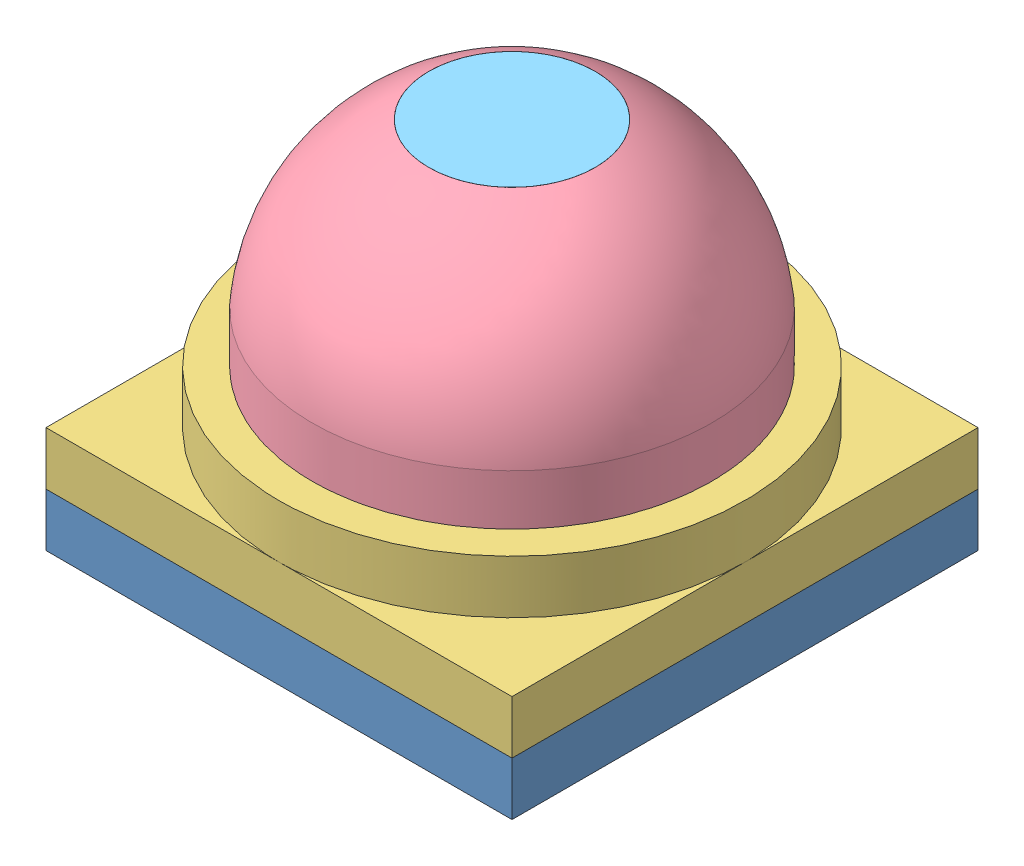
SolidWorks assembly Magnetic Force Sensor Assembly, configuration Default. Lengths in mm.
Overall size (15.86 11.22 15.86).
5 component instances, 5 part files, 9 mates.
Components (placement in the parent):
- PCB with O-Ring-1: PCB with O-Ring [Default] at (5.9128 5.0008 11.2365) size (14 2.1 14)
- MLX90393 Magnetometer-1: MLX90393 Magnetometer [Default] at (5.9128 6.6008 11.2365) x (0 0 1) z (-1 0 0) size (2.1 0.56 2.6)
- Elastomer PCB Interface-1: Elastomer PCB Interface [Default] at (5.9128 6.6008 11.2365) size (14 3.2 14)
- Silicon Elastomer-1: Silicon Elastomer [Default] at (5.9128 8.3185 11.2365) x (0.912613 0 -0.408824) z (0 -1 0) size (12 12 7.9)
- Neodymium Magnet-1: Neodymium Magnet [Default] at (5.9128 14.2185 11.2365) size (5 2 5)
Mates (geometry in assembly coordinates):
- Coincident1: coincident anti-aligned: plane of PCB with O-Ring-1 through (5.9128 6.6008 11.2365) normal (0 1 0); plane of MLX90393 Magnetometer-1 through (5.9128 6.6008 11.2365) normal (0 -1 0)
- Distance1: distance = 5.95 mm: plane of PCB with O-Ring-1 through (-1.0872 6.6008 4.2365) normal (0 0 -1); line of MLX90393 Magnetometer-1 through (7.2128 6.6008 10.1865) axis (-1 0 0)
- Distance2: distance = 5.7 mm aligned: plane of MLX90393 Magnetometer-1 through (7.2128 7.0008 10.1865) normal (1 0 0); plane of PCB with O-Ring-1 through (12.9128 6.6008 18.2365) normal (1 0 0)
- Coincident5: coincident anti-aligned: plane of PCB with O-Ring-1 through (5.9128 6.6008 11.2365) normal (0 1 0); plane of Elastomer PCB Interface-1 through (5.9128 6.6008 11.2365) normal (0 -1 0)
- Coincident6: coincident aligned: plane of PCB with O-Ring-1 through (-1.0872 6.6008 18.2365) normal (0 0 1); plane of Elastomer PCB Interface-1 through (-1.0872 8.2008 18.2365) normal (0 0 1)
- Coincident7: coincident aligned: plane of PCB with O-Ring-1 through (-1.0872 6.6008 18.2365) normal (-1 0 0); plane of Elastomer PCB Interface-1 through (-1.0872 8.2008 18.2365) normal (-1 0 0)
- Concentric2: concentric anti-aligned: cylinder of Elastomer PCB Interface-1 through (5.9128 9.8008 11.2365) axis (0 -1 0) radius 6; cylinder of Silicon Elastomer-1 through (5.9128 14.2185 11.2365) axis (0 1 0) radius 6
- Coincident9: coincident aligned: plane of Silicon Elastomer-1 through (5.9128 14.2185 11.2365) normal (0 1 0); circle of Neodymium Magnet-1
- Concentric3: concentric anti-aligned: cylinder of Silicon Elastomer-1 through (5.9128 14.2185 11.2365) axis (0 1 0) radius 2.5; cylinder of Neodymium Magnet-1 through (5.9128 16.2185 11.2365) axis (0 -1 0) radius 2.5
